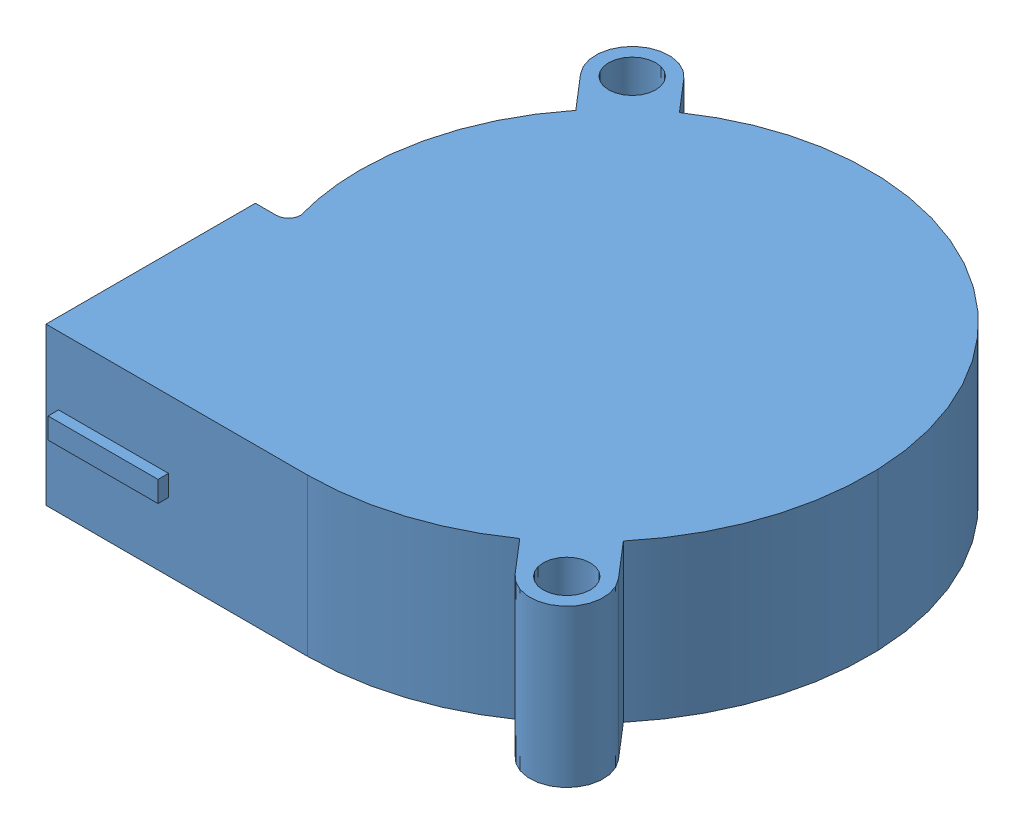
SolidWorks assembly Assem1, configuration Default. Lengths in mm.
Overall size (51.77 15 53.05).
2 component instances, 2 part files, 4 mates.
Components (placement in the parent):
- Blower Fan - Squirrel Fan-1: Blower Fan - Squirrel Fan [Default] at (26.434 29.983 35.6608) size (51.77 15 53.05)
- PlasPrint-Fan Vent v1-1: PlasPrint-Fan Vent v1 [Default] at (26.434 37.483 35.6608) x (1 0 0) z (0 1 0) size (49.25 52 0)
Mates (geometry in assembly coordinates):
- InPlace1: in place: plane of Blower Fan - Squirrel Fan-1 through (27.7184 37.483 35.6608) normal (0 1 0); plane of ? through (0 37.483 0) normal (0 1 0); moOrthogonalPlaneRef_w of Blower Fan - Squirrel Fan-1 through (27.7184 37.483 35.6608) normal (0 1 0); plane of ? through (0 37.483 0) normal (0 0 -1); plane of Blower Fan - Squirrel Fan-1 through (27.7184 37.483 35.6608) normal (0 1 0); line of ? through (-55 0 37.483) axis (0 1 0); plane of Blower Fan - Squirrel Fan-1 through (27.7184 37.483 35.6608) normal (0 1 0); unknown of PlasPrint-Fan Vent v1-1
- Coincident1: coincident aligned: plane of Blower Fan - Squirrel Fan-1; plane of PlasPrint-Fan Vent v1-1
- Coincident2: coincident aligned: moOrthogonalPlaneRef_w of Blower Fan - Squirrel Fan-1 through (26.434 37.483 35.6608) normal (0 0 -1); plane of PlasPrint-Fan Vent v1-1 through (26.434 37.483 35.6608) normal (0 0 -1)
- Coincident3: coincident anti-aligned: moOrthogonalPlaneRef_w of Blower Fan - Squirrel Fan-1 through (26.434 37.483 35.6608) normal (-1 0 0); plane of PlasPrint-Fan Vent v1-1
